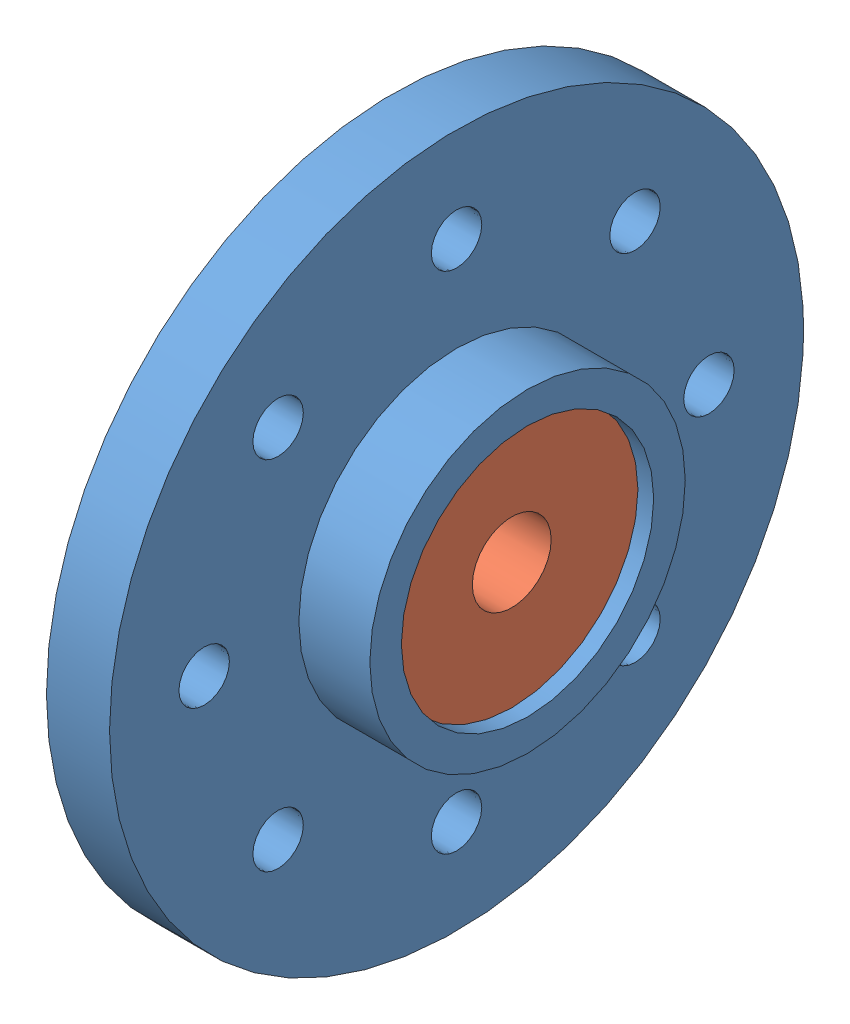
SolidWorks assembly As_back_horn_28_001, configuration Default. Lengths in mm.
Overall size (5.5 22 22).
2 component instances, 2 part files, 0 mates.
Components (placement in the parent):
- back_horn_28_001-1: back_horn_28_001 [Default] at origin size (5.5 22 22)
- bearing_2.5_8_3-1: bearing_2.5_8_3 [Default] at (2 0 0) size (3 8 8)
